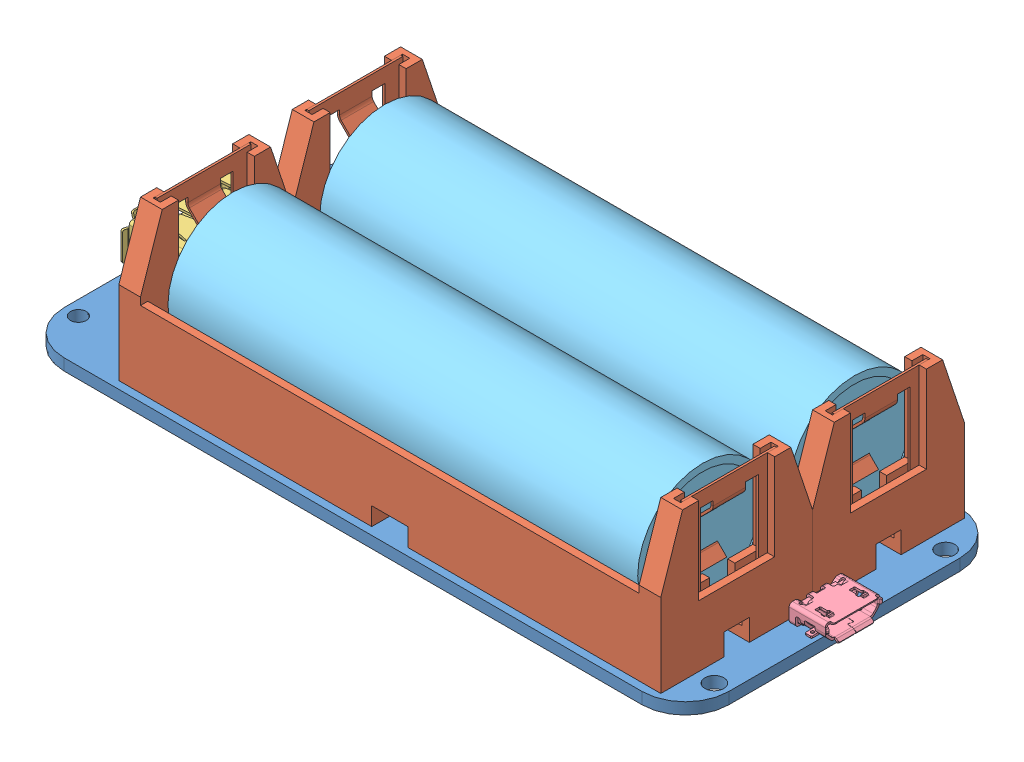
SolidWorks assembly Battery_Board_Assembly, configuration Default. Lengths in mm.
Overall size (94.33 25.21 44).
8 component instances, 6 part files, 15 mates.
Components (placement in the parent):
- pcb-1: pcb [Default] at (22.3065 49.1152 63.1264) size (92 1.6 44)
- 18650 Single Cell Holder-1: 18650 Single Cell Holder [Default<As Welded><As Machined>] at (72.346 50.2152 30.5745) size (75 21 21)
- femaleThruHoleUSB-1: femaleThruHoleUSB [Default] at (22.2417 53.5852 41.4718) x (0 0 1) z (0 1 0) size (15.78 14.44 11.13)
- 18650 Single Cell Holder-2: 18650 Single Cell Holder [Default<As Welded><As Machined>] at (72.346 50.2152 51.5745) size (75 21 21)
- Parts - micro_B-1: Parts - micro_B [기본] at (110.1061 50.3402 41.1264) x (0 0 -1) z (1 0 0) size (7.92 3.01 5.67)
- Part1^Battery_Board_Assembly-1: Part1^Battery_Board_Assembly [Default] at origin (virtual)
- 18650-1: 18650 [Default] at (105.146 61.7152 30.5745) x (0 1 0) z (0 0 1) size (18 65 18)
- 18650-2: 18650 [Default] at (105.146 61.7152 51.5745) x (0 1 0) z (0 0 1) size (18 65 18)
Mates (geometry in assembly coordinates):
- Parallel1: parallel aligned: plane of pcb-1 through (22.3065 50.7152 63.1264) normal (-1 0 0); plane of femaleThruHoleUSB-1 through (22.2417 53.5852 41.4718) normal (-1 0 0)
- Coincident5: coincident anti-aligned: plane of pcb-1 through (22.3065 50.7152 63.1264) normal (0 1 0); plane of femaleThruHoleUSB-1 through (22.2417 50.7152 47.6218) normal (0 -1 0)
- Lock1: lock: unknown of pcb-1; unknown of femaleThruHoleUSB-1
- Coincident9: coincident anti-aligned: plane of pcb-1 through (22.3065 50.7152 63.1264) normal (0 1 0); plane of 18650 Single Cell Holder-1 through (72.346 50.7152 30.5745) normal (0 -1 0)
- Coincident10: coincident anti-aligned: plane of pcb-1 through (22.3065 50.7152 63.1264) normal (0 1 0); plane of 18650 Single Cell Holder-2 through (72.346 50.7152 51.5745) normal (0 -1 0)
- Lock2: lock: unknown of pcb-1; unknown of 18650 Single Cell Holder-1
- Coincident12: coincident anti-aligned: plane of 18650 Single Cell Holder-1 through (34.846 71.2152 41.0745) normal (0 0 1); plane of 18650 Single Cell Holder-2 through (34.846 71.2152 41.0745) normal (0 0 -1)
- Coincident13: coincident aligned: plane of 18650 Single Cell Holder-1 through (109.846 71.2152 41.0745) normal (1 0 0); plane of 18650 Single Cell Holder-2 through (109.846 71.2152 62.0745) normal (1 0 0)
- Coincident14: coincident anti-aligned: plane of pcb-1 through (22.3065 50.7152 63.1264) normal (0 1 0); plane of Parts - micro_B-1 through (111.5301 50.7152 40.1782) normal (0 -1 0)
- Parallel2: parallel aligned: line of pcb-1 through (114.3065 50.7152 57.1264) axis (0 0 -1); line of Parts - micro_B-1 through (116.0166 50.656 43.3764) axis (0 0 -1)
- Width1: width anti-aligned: plane of pcb-1 through (22.3065 50.7152 19.1264) normal (0 0 -1); plane of pcb-1 through (22.3065 50.7152 63.1264) normal (0 0 1); plane of Parts - micro_B-1 through (110.3061 51.9652 44.8764) normal (0 0 1); plane of Parts - micro_B-1 through (115.5061 51.9652 37.3764) normal (0 0 -1)
- Concentric1: concentric: cylinder of 18650 Single Cell Holder-1 through (133.7161 61.7152 30.5745) axis (-1 0 0) radius 9.5; cylinder of 18650-1 through (40.146 61.7152 30.5745) axis (1 0 0) radius 9
- Coincident15: coincident anti-aligned: plane of 18650 Single Cell Holder-1 through (40.146 51.7957 30.5745) normal (1 0 0); plane of 18650-1 through (40.146 61.7152 30.5745) normal (-1 0 0)
- Concentric2: concentric: cylinder of 18650 Single Cell Holder-2 through (133.7161 61.7152 51.5745) axis (-1 0 0) radius 9.5; cylinder of 18650-2 through (98.4676 61.7152 51.5745) axis (1 0 0) radius 9
- Coincident16: coincident anti-aligned: plane of 18650 Single Cell Holder-2 through (40.146 51.7957 51.5745) normal (1 0 0); plane of 18650-2 through (40.146 61.7152 51.5745) normal (-1 0 0)
